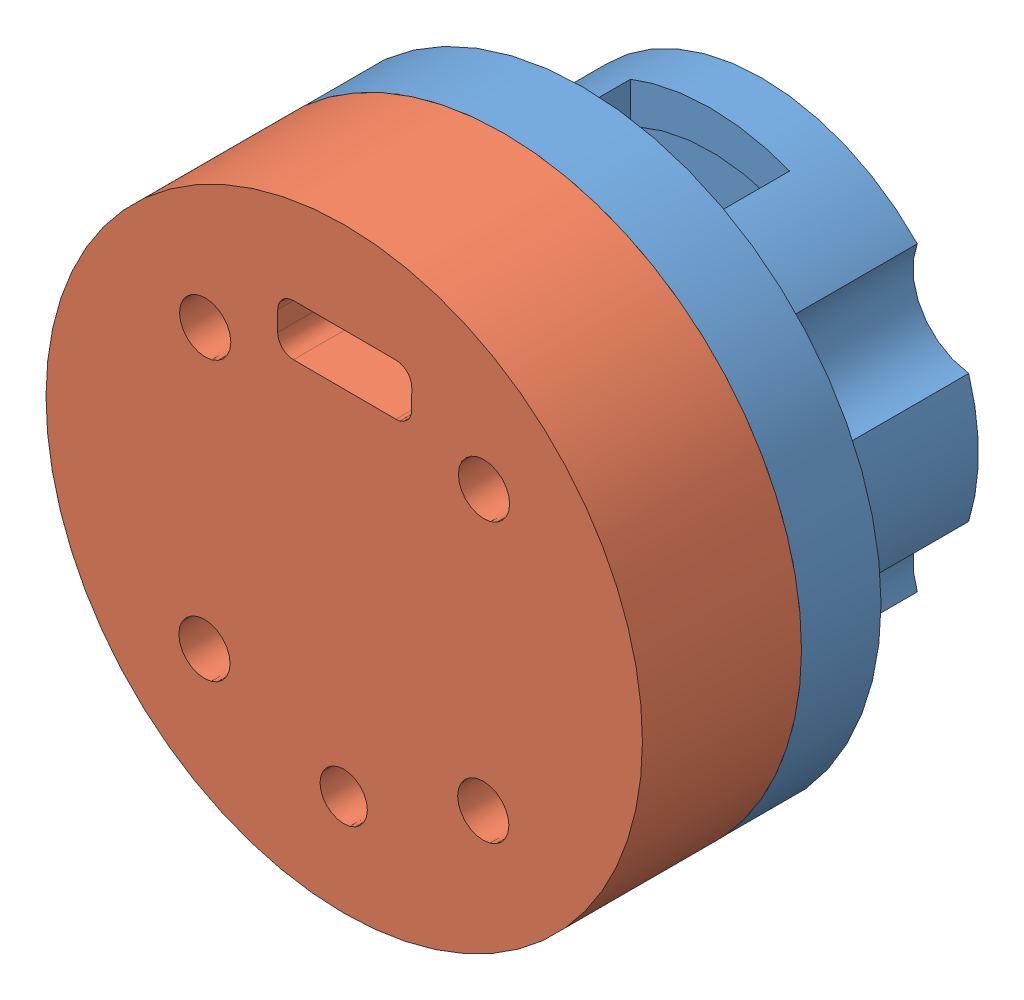
SolidWorks assembly 装配体4, configuration 默认. Lengths in mm.
Overall size (75.2 75.2 52.5).
2 component instances, 2 part files, 2 mates.
Components (placement in the parent):
- kinova_connect-1: kinova_connect [默认] at (2.2483 9.268 -3.75) size (75 75 32.5)
- connectorbase0-1: connectorbase0 [默认] at (2.2483 9.268 26.25) x (-0.002634 -0.999997 0) z (0 0 -1) size (75 75 20)
Mates (geometry in assembly coordinates):
- 重合1: coincident anti-aligned: plane of kinova_connect-1 through (2.2483 9.268 16.25) normal (0 0 1); plane of connectorbase0-1 through (2.2483 9.268 16.25) normal (0 0 -1)
- 同心2: concentric aligned: cylinder of kinova_connect-1 through (2.2483 9.268 16.25) axis (0 0 -1) radius 37.5; cylinder of connectorbase0-1 through (2.2483 9.268 36.25) axis (0 0 -1) radius 37.5
